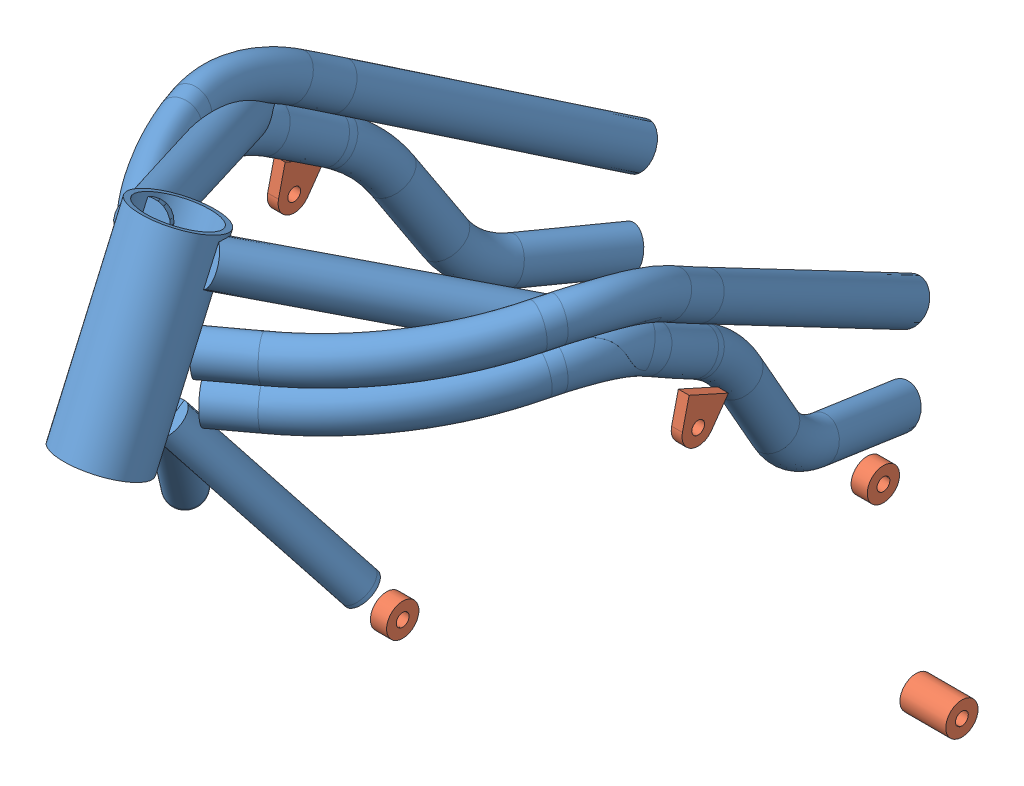
SolidWorks assembly Frame Reference, configuration Default. Lengths in mm.
Overall size (417.27 2237.96 2872.61).
2 component instances, 2 part files, 2 mates.
Components (placement in the parent):
- Frame Reference-1: Frame Reference [Default] at origin size (417.27 2237.96 2872.61)
- Mounting Points-1: Mounting Points [Default] at (182.25 669.384 -912.0574) x (1 0 0) z (0 -0.100098 0.994978) size (384.5 468.14 499.84)
Mates (geometry in assembly coordinates):
- Coincident1: coincident: plane of assembly through (0 0 0) normal (1 0 0); plane of Mounting Points-1 through (0 669.384 -912.0574) normal (-1 0 0); plane of assembly
- Coincident4: coincident: point of assembly; point of Mounting Points-1; line of assembly
